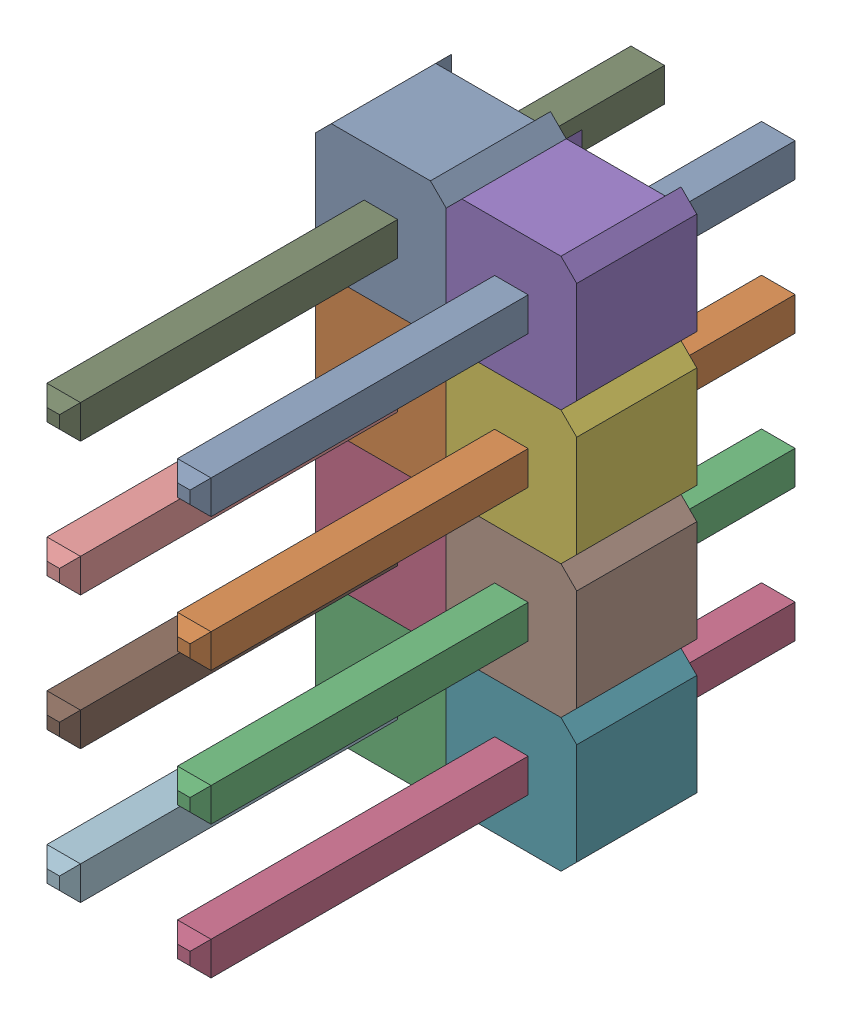
SolidWorks assembly 254-4X2, configuration 默认. Lengths in mm.
Overall size (4.98 10.16 11.54).
7 component instances, 2 part files, 0 mates.
Components (placement in the parent):
- User Library-2.54mm Male Header (4x2)-1: User Library-2.54mm Male Header (4x2) [默认] at (-0.65 31.8 -15.24) x (0 1 0) z (0 0 1) size (10.16 4.98 11.54)
  - User Library-Header_Male_4Pin-1: User Library-Header_Male_4Pin [默认] at (-35.6012 -1.8987 15.2958) size (10.16 2.49 11.54)
    - User Library-Header_Male_4Pin_PinArray-1: User Library-Header_Male_4Pin_PinArray [默认] at origin size (8.26 0.64 11.54)
    - User Library-Header_Male_4Pin_BodyArray-1: User Library-Header_Male_4Pin_BodyArray [默认] at origin size (10.16 2.49 2.29)
  - User Library-Header_Male_4Pin-1-1: User Library-Header_Male_4Pin-1 [默认] at (-35.6012 0.5913 15.2958) size (10.16 2.49 11.54)
    - User Library-Header_Male_4Pin_PinArray-1: User Library-Header_Male_4Pin_PinArray [默认] at origin size (8.26 0.64 11.54)
    - User Library-Header_Male_4Pin_BodyArray-1: User Library-Header_Male_4Pin_BodyArray [默认] at origin size (10.16 2.49 2.29)
